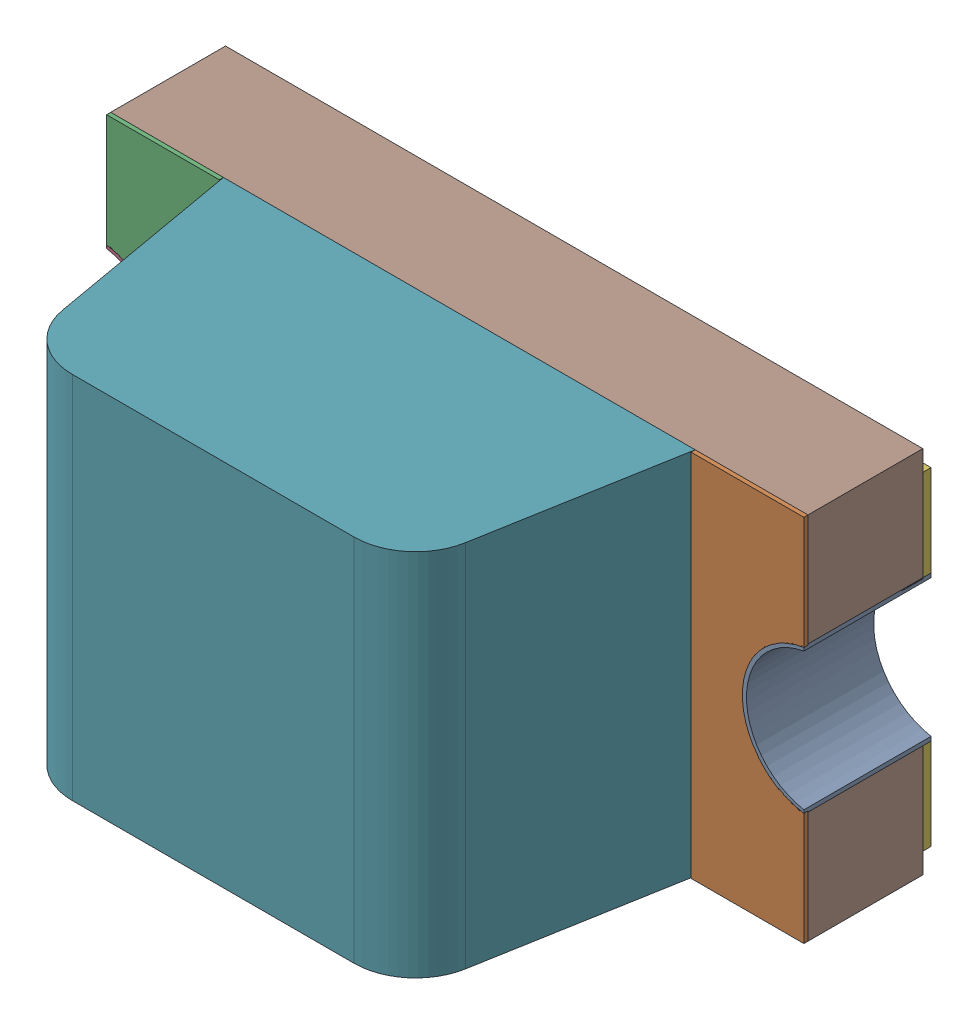
SolidWorks assembly LED1主板_V1.0, configuration 默认. Lengths in mm.
Overall size (1.7 0.9 0.9).
7 component instances, 6 part files, 0 mates.
Components (placement in the parent):
- LED-GREEN-0603-1: LED-GREEN-0603 [默认] at (65.797 47.2433 0) x (0 -1 0) z (0 0 1) size (0.9 1.7 0.9)
  - User_Library-LTST-C190GKT_Pad005-1: User_Library-LTST-C190GKT_Pad005 [默认] at origin size (0.35 0.15 0.31)
  - User_Library-LTST-C190GKT_Pad001-1: User_Library-LTST-C190GKT_Pad001 [默认] at origin size (0.9 1.7 0.01)
  - User_Library-LTST-C190GKT_Pad004-1: User_Library-LTST-C190GKT_Pad004 [默认] at origin size (0.35 0.15 0.31)
  - User_Library-LTST-C190GKT_Pad003-1: User_Library-LTST-C190GKT_Pad003 [默认] at origin size (0.8 1.7 0.02)
  - User_Library-LTST-C190GKT_Lens-1: User_Library-LTST-C190GKT_Lens [默认] at origin size (0.9 1.15 0.6)
  - User_Library-LTST-C190GKT_Pad-1: User_Library-LTST-C190GKT_Pad [默认] at origin size (0.9 1.7 0.28)
